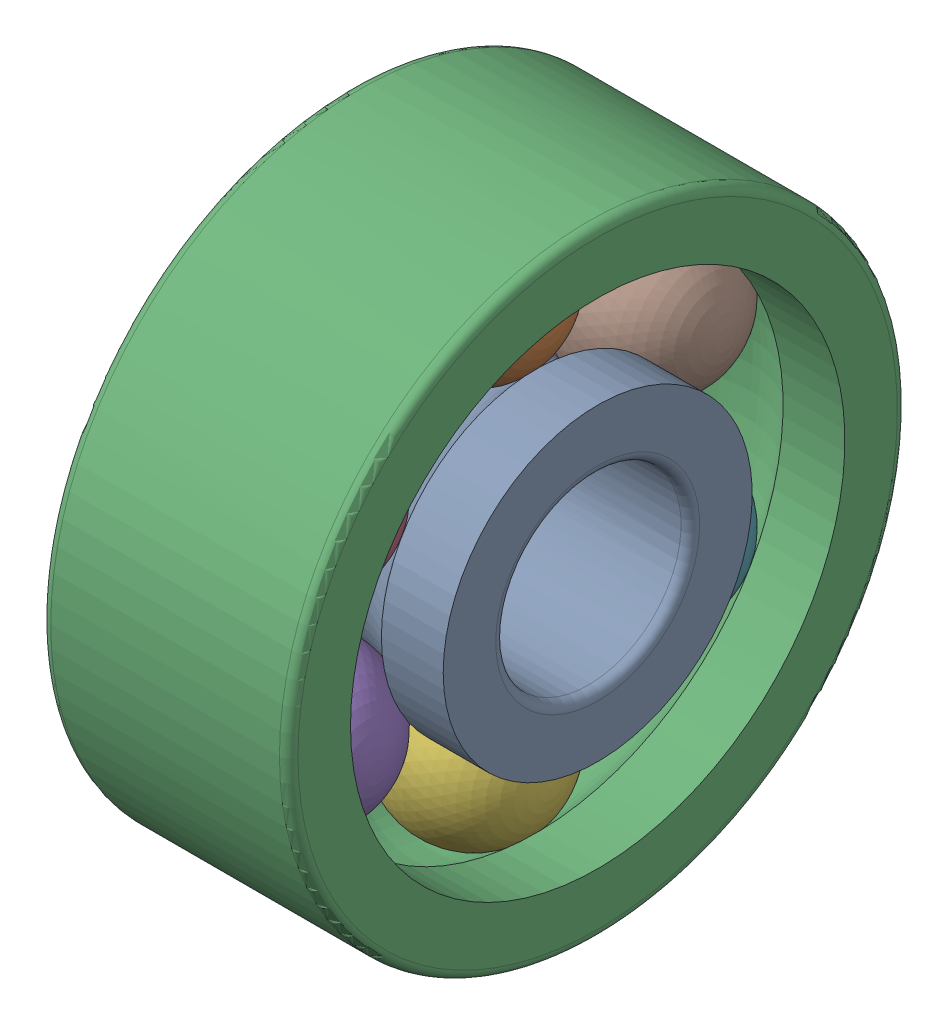
SolidWorks assembly Roul-bille-2-moteur-, configuration Défaut. Lengths in mm.
Overall size (4 10 10).
8 component instances, 3 part files, 12 mates.
Components (placement in the parent):
- bague-int-moteur-2-1: bague-int-moteur-2 [Défaut] at origin size (4 5 5)
- Bille-moteur-2-1: Bille-moteur-2 [Défaut] at origin size (2.5 2.5 2.5)
- bague-ext-moteur-2-1: bague-ext-moteur-2 [Défaut] at origin size (4 10 10)
- Bille-moteur-2-2: Bille-moteur-2 [Défaut] x (1 0 0) z (0 -0.866025 0.5) size (2.5 2.5 2.5)
- Bille-moteur-2-3: Bille-moteur-2 [Défaut] x (1 0 0) z (0 -0.866025 -0.5) size (2.5 2.5 2.5)
- Bille-moteur-2-4: Bille-moteur-2 [Défaut] x (1 0 0) z (0 0 -1) size (2.5 2.5 2.5)
- Bille-moteur-2-5: Bille-moteur-2 [Défaut] x (1 0 0) z (0 0.866025 -0.5) size (2.5 2.5 2.5)
- Bille-moteur-2-6: Bille-moteur-2 [Défaut] x (1 0 0) z (0 0.866025 0.5) size (2.5 2.5 2.5)
Mates (geometry in assembly coordinates):
- Sur place1: in place: plane of ?; moOrthogonalPlaneRef_w of ? through (-1000 0 0) axis (0 0 1); line of ? through (1000 -1000 0) axis (0 0 1); unknown of ?
- Coïncidente1: coincident aligned: plane of bague-int-moteur-2-1; plane of assembly
- Coïncidente2: coincident aligned: plane of ? through (0 0 0) normal (0 1 0)
- Coïncidente3: coincident anti-aligned: plane of ? through (0 0 0) normal (1 0 0)
- Sur place2: in place: line of ? through (0 0 0) axis (0 0 1); line of ? through (-1000 0 0) axis (0 0 1); line of ? through (1000 -1000 0) axis (0 0 1); unknown of ?
- Coïncidente4: coincident aligned: plane of Bille-moteur-2-1; plane of assembly
- Coïncidente5: coincident aligned: plane of ? through (0 0 0) normal (0 1 0)
- Coïncidente6: coincident anti-aligned: plane of ? through (0 0 0) normal (1 0 0)
- Sur place3: in place: line of ? through (0 0 0) axis (0 0 1); line of ? through (-1000 0 0) axis (0 0 1); line of ? through (1000 -1000 0) axis (0 0 1); unknown of ?
- Coïncidente7: coincident aligned: plane of bague-ext-moteur-2-1; plane of assembly
- Coïncidente8: coincident aligned: plane of ? through (0 0 0) normal (0 1 0)
- Coïncidente9: coincident anti-aligned: plane of ? through (0 0 0) normal (1 0 0)
